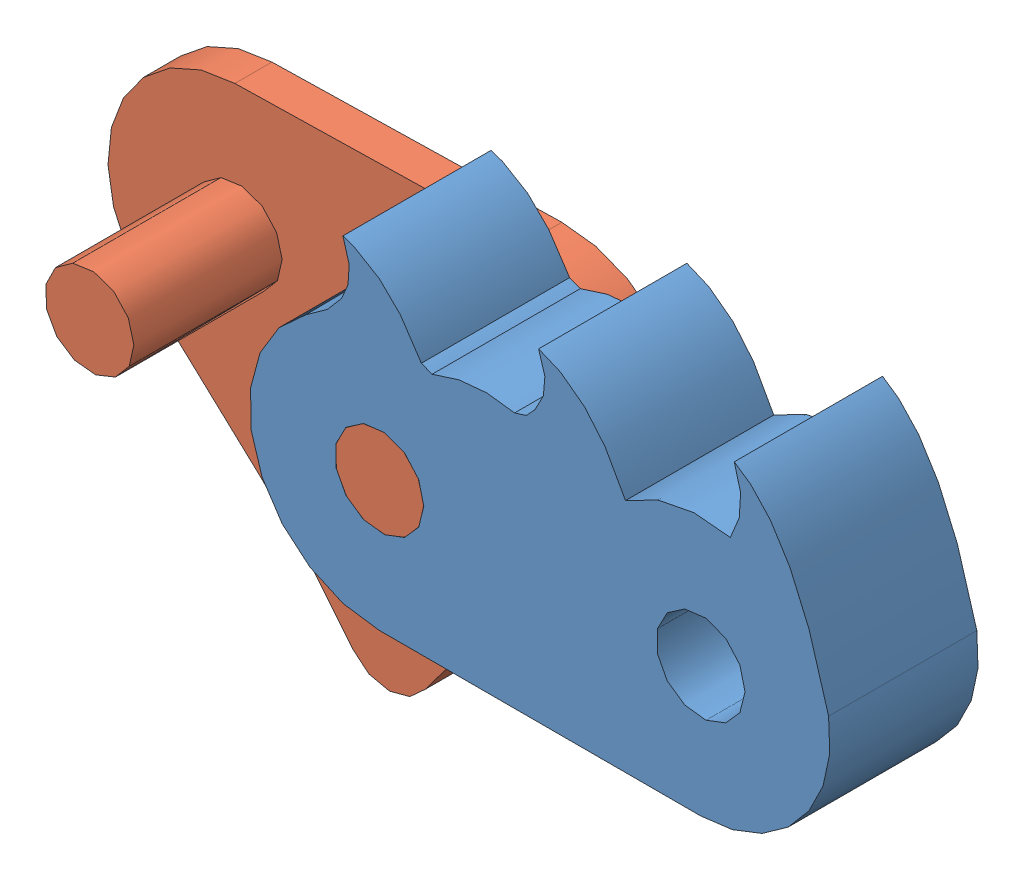
SolidWorks assembly Assem1, configuration Default. Lengths in mm.
Overall size (11.78 7.08 2.5).
2 component instances, 2 part files, 2 mates.
Components (placement in the parent):
- Teeth-1: Teeth [Default] at (0.7324 7.7222 8.0114) size (7.83 4.36 2)
- Inner Part-1: Inner Part [Default] at (0.733 7.6685 7.5114) x (0.999772 0.021364 0) z (0 0 1) size (7.41 6.1 2.5)
Mates (geometry in assembly coordinates):
- Concentric1: concentric: cylinder of Teeth-1 through (3.2482 7.7222 8.0114) axis (0 0 1) radius 0.6; cylinder of Inner Part-1 through (3.2482 7.7222 7.5114) axis (0 0 1) radius 0.6
- Coincident1: coincident: plane of Teeth-1 through (0.7324 7.7222 10.0114) normal (0 0 1); plane of Inner Part-1 through (3.2482 7.7222 10.0114) normal (0 0 1)
